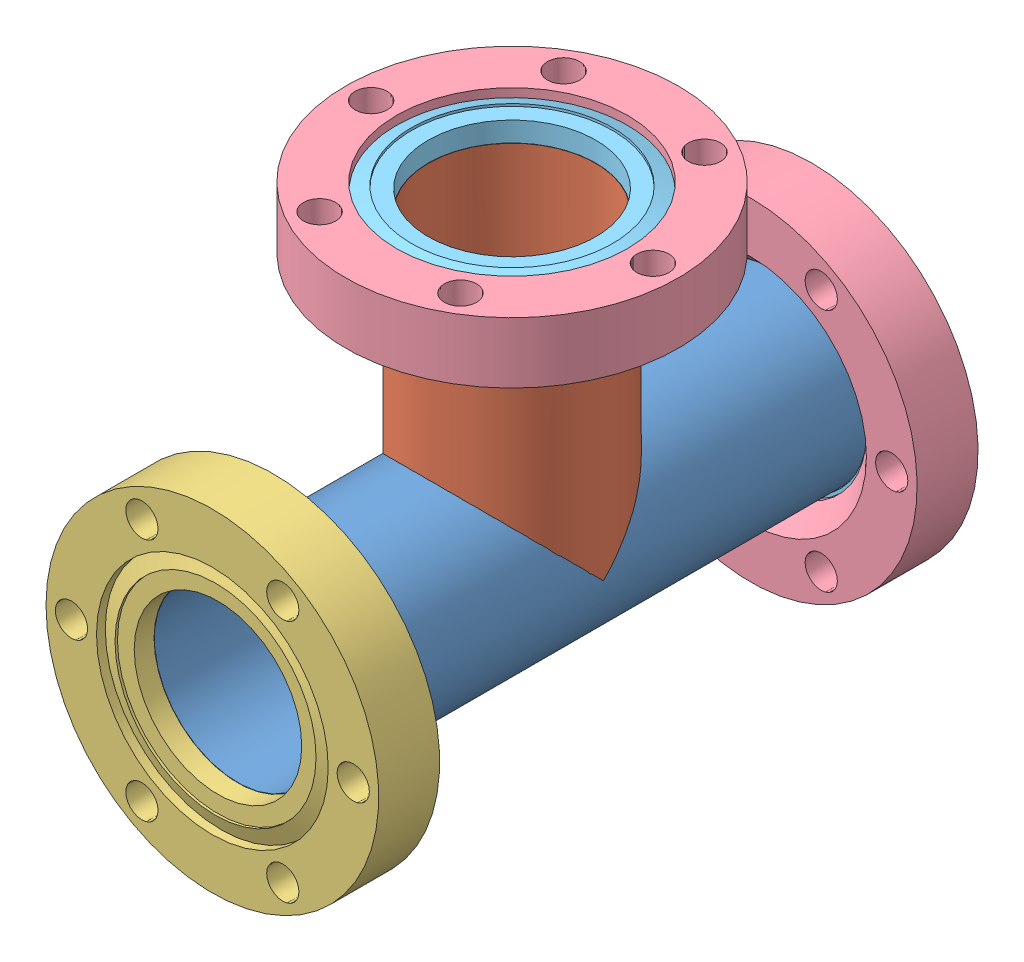
SolidWorks assembly 404002, configuration Default. Lengths in mm.
Overall size (69.34 97.13 124.92).
9 component instances, 5 part files, 0 mates.
Components (placement in the parent):
- 404002-001-1: 404002-001 [Default] at origin size (38.1 38.1 114.3)
- 404002-002-1: 404002-002 [Default] at (0 0 57.15) x (-1 0 0) z (0 1 0) size (38.1 38.1 58.86)
- 110014 (2.75 X 1.5 NR)-1: 110014 (2.75 X 1.5 NR) [Default] at (0 0 113.2586) x (0 0 1) z (-1 0 0) size (12.7 69.34 69.34)
- 100014 (2.75 X 1.5 R)-1: 100014 (2.75 X 1.5 R) [Default] at (0 62.4586 57.15) x (0 -1 0) z (1 0 0) size (12.7 69.34 69.34)
  - 100014 (2.75 X 1.5 REC)-1: 100014 (2.75 X 1.5 REC) [Default] at origin size (12.7 69.34 69.34)
  - 100014 (2.75 X 1.5 INS)-1: 100014 (2.75 X 1.5 INS) [Default] at (1.17 0 0) x (1 0 0) z (0 0.994423 -0.105464) size (6.96 48.1 48.1)
- 100014 (2.75 X 1.5 R)-2: 100014 (2.75 X 1.5 R) [Default] at (0 0 -5.3086) x (0 0 1) z (-1 0 0) size (12.7 69.34 69.34)
  - 100014 (2.75 X 1.5 REC)-1: 100014 (2.75 X 1.5 REC) [Default] at origin size (12.7 69.34 69.34)
  - 100014 (2.75 X 1.5 INS)-1: 100014 (2.75 X 1.5 INS) [Default] at (1.17 0 0) x (1 0 0) z (0 0.994423 -0.105464) size (6.96 48.1 48.1)
